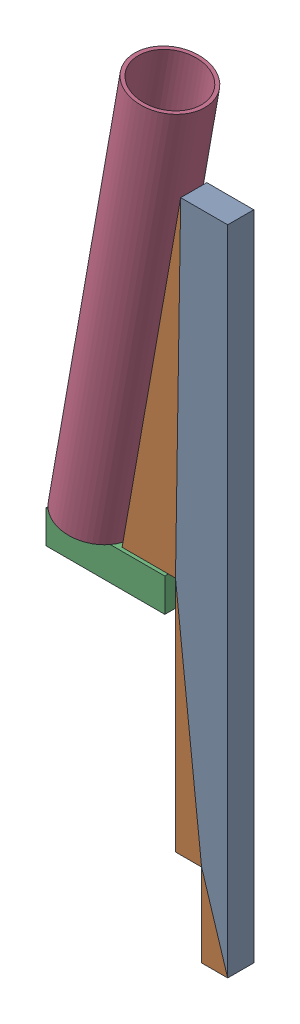
SolidWorks assembly SupportEau v9-3, configuration Défaut. Lengths in mm.
Overall size (150.06 625.45 60).
3 component instances, 3 part files, 0 mates.
Components (placement in the parent):
- SupportEau1 v7-1: SupportEau1 v7 [Défaut] at (-562.0102 0 411.6666) x (-1 0 0) z (0 -1 0) size (89 22 550)
- SupportEau2 v5-1: SupportEau2 v5 [Défaut] at (-626.0102 242 400.6666) x (-1 0 0) z (0 0 -1) size (100 28 28)
- SupportEau3 v3-1: SupportEau3 v3 [Défaut] at (-621.7472 620.2395 400.6666) x (-0.984808 0.173648 0) z (0 0 1) size (60 350 60)
